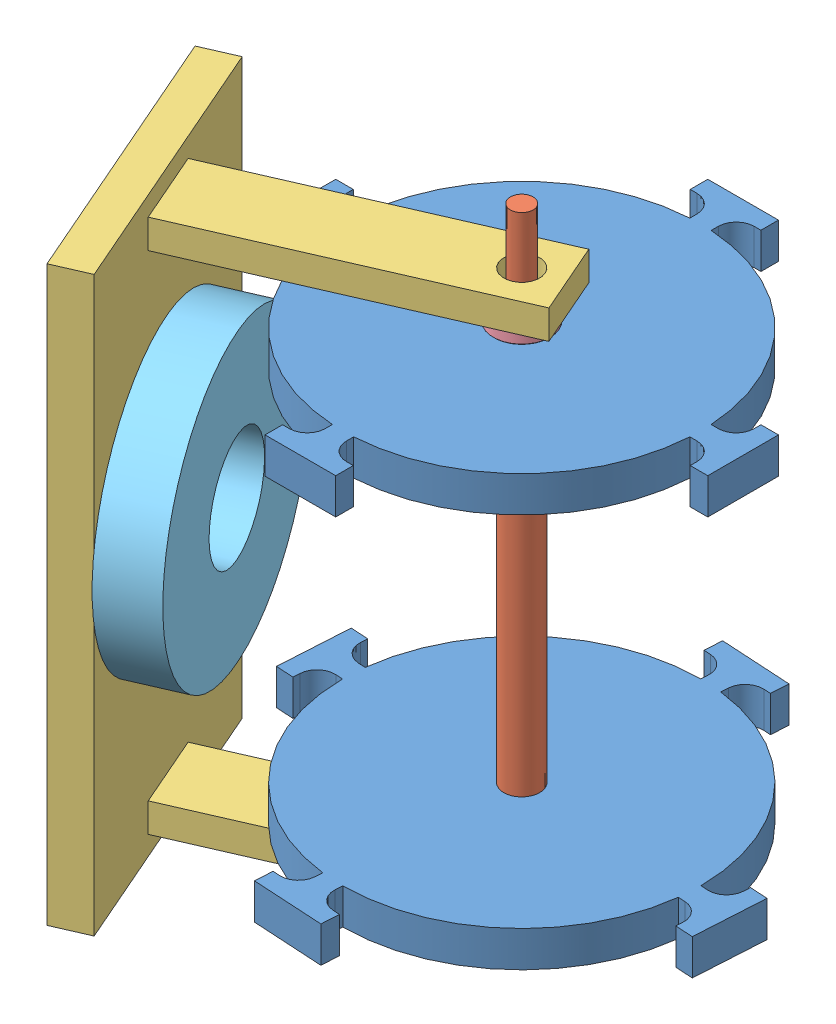
SolidWorks assembly Motor Assembly, configuration Default. Lengths in mm.
Overall size (150.62 180 137.89).
7 component instances, 5 part files, 10 mates.
Components (placement in the parent):
- Motor circular part-1: Motor circular part [Default] at (108.2416 111.0977 190.2124) size (107.29 10 107.29)
- motor inner rod-1: motor inner rod [Default] at (108.2416 61.0977 190.2124) x (-0.923372 0 -0.383907) z (0.383907 0 -0.923372) size (10 180 10)
- Motor circular part-3: Motor circular part [Default] at (108.2416 1.0977 190.2124) x (-0.998254 0 -0.059074) z (0.059074 0 -0.998254) size (107.29 10 107.29)
- motor casing-1: motor casing [Default] at (30.3336 60.8755 224.2028) x (0 -1 0) z (0.399886 0 0.916565) size (160 95 80)
- 60355K701_BALL BEARING-1: 60355K701_BALL BEARING [60355K701] at (108.2416 124.919 190.2124) x (0.508594 0 -0.861007) z (0 1 0) size (15.88 15.88 4.98)
- 60355K701_BALL BEARING-2: 60355K701_BALL BEARING [60355K701] at (108.2416 -3.168 190.2124) x (1 0 0) z (0 1 0) size (15.88 15.88 4.98)
- motor magnet-1: motor magnet [Default] at (39.9405 65.145 221.2152) x (-0.344968 -0.505777 -0.790688) z (0.916565 0 -0.399886) size (80 80 15)
Mates (geometry in assembly coordinates):
- Coincident6: coincident aligned: plane of Motor circular part-1 through (108.2416 121.0977 190.2124) normal (0 1 0); plane of motor inner rod-1 through (108.2416 121.0977 190.2124) normal (0 1 0)
- Concentric2: concentric anti-aligned: cylinder of Motor circular part-1 through (108.2416 121.0977 190.2124) axis (0 -1 0) radius 5; circle of motor inner rod-1
- Coincident7: coincident aligned: plane of motor inner rod-1 through (108.2416 1.0977 190.2124) normal (0 -1 0); plane of Motor circular part-3 through (108.2416 1.0977 190.2124) normal (0 -1 0)
- Concentric3: concentric anti-aligned: circle of motor inner rod-1; cylinder of Motor circular part-3 through (108.2416 11.0977 190.2124) axis (0 -1 0) radius 5
- Concentric4: concentric anti-aligned: circle of motor inner rod-1; cylinder of motor casing-1 through (108.2416 140.8755 190.2124) axis (0 -1 0) radius 4.9732
- Concentric5: concentric anti-aligned: cylinder of motor inner rod-1 through (108.2416 151.0977 190.2124) axis (0 -1 0) radius 3.175; cylinder of 60355K701_BALL BEARING-1 through (108.2416 127.4082 190.2124) axis (0 1 0) radius 3.175
- Concentric6: concentric anti-aligned: cylinder of motor inner rod-1 through (108.2416 151.0977 190.2124) axis (0 -1 0) radius 3.175; cylinder of 60355K701_BALL BEARING-2 through (108.2416 -0.6788 190.2124) axis (0 1 0) radius 3.175
- Coincident9: coincident anti-aligned: plane of motor casing-1 through (113.0957 -5.6572 176.3311) normal (0 1 0); plane of 60355K701_BALL BEARING-2 through (108.2416 -5.6572 186.7885) normal (0 -1 0)
- Coincident11: coincident anti-aligned: plane of motor casing-1 through (113.0957 127.4082 176.3311) normal (0 -1 0); plane of 60355K701_BALL BEARING-1 through (103.8701 127.4082 187.6302) normal (0 1 0)
- Coincident12: coincident anti-aligned: plane of motor casing-1 through (39.4993 60.8755 220.2039) normal (0.916565 0 -0.399886); plane of motor magnet-1 through (39.9405 65.145 221.2152) normal (-0.916565 0 0.399886)
